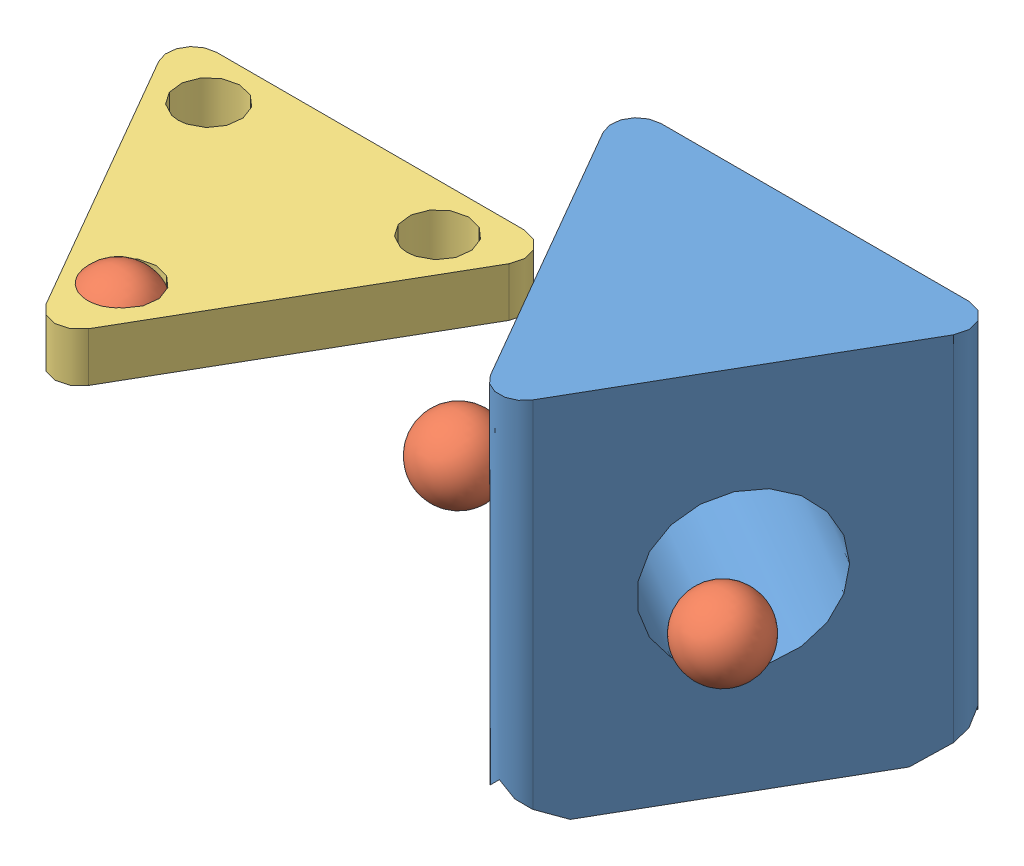
SolidWorks assembly MountingScheme, configuration Default. Lengths in mm.
Overall size (32.59 15 12.9).
5 component instances, 3 part files, 0 mates.
Components (placement in the parent):
- TricornerGround-1: TricornerGround [Default] at (0.5614 -5.8955 3.7091) size (14.54 15 12.86)
- EighthBall-1: EighthBall [Default] at (-16.9862 1.6045 6.8342) size (3.17 3.17 3.17)
- EighthBall-2: EighthBall [Default] at (6.6862 1.6045 5.8861) size (3.17 3.17 3.17)
- EighthBall-3: EighthBall [Default] at (-4.9658 1.6045 4.9897) size (3.17 3.17 3.17)
- TricornerHat-1: TricornerHat [Default] at (-17.494 0.6045 3.748) size (14.54 2 12.86)
